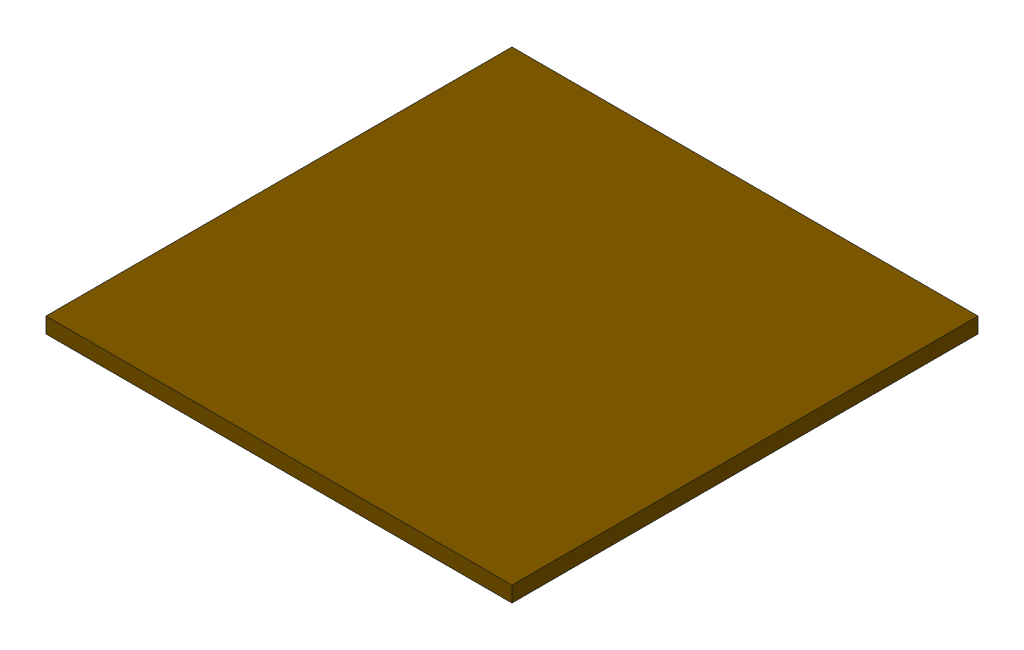
SolidWorks assembly Main, configuration Default. Lengths in mm.
Overall size (300 156.81 300).
28 component instances, 18 part files, 53 mates.
Components (placement in the parent):
- PCB Outline v2-1: PCB Outline v2 [Default] at (-204.6573 359.2856 0) x (-0.0002 0 1) z (-1 0 -0.0002) size (100 3 100)
- RolyPoly PCB v1 SLDWRKS-1: RolyPoly PCB v1 SLDWRKS [Default] at (-151.3038 354.2331 -67.2993) x (-0.0002 0 1) z (0 -1 0) size (100 100 1.64)
  - RolyPoly PCB v1.step-1: RolyPoly PCB v1.step [Default] at origin size (100 100 1.64)
    - Board.step-1: Board.step [Default] at origin size (100 100 1.5)
    - 1-copper.step-1: 1-copper.step [Default] at (0 0 1.5) size (91.04 84.59 0.07)
    - 16-copper.step-1: 16-copper.step [Default] at (0 0 -0.035) size (97.81 97.81 0.07)
    - 1-soldermask.step-1: 1-soldermask.step [Default] at (0 0 1.5) size (100 100 0.05)
    - 16-soldermask.step-1: 16-soldermask.step [Default] at origin size (100 100 0.05)
- N20 Motor Mount-1: N20 Motor Mount [Default] at (-210.7573 401.2856 3) x (1 0 0) z (0 0 -1) size (34.2 12 12)
- N20 Motor Mount-2: N20 Motor Mount [Default] at (-198.5573 401.2856 -3) x (-1 0 0) z (0 0 1) size (34.2 12 12)
- Motor2-1: Motor2 [Default] at (-198.5573 398.2856 -6.9) x (0 -1 0) z (0 0 -1) size (10 12 34)
- Motor2-2: Motor2 [Default] at (-210.7573 398.2856 6.9) x (0 -1 0) z (0 0 1) size (10 12 34)
- 18650 Battery Holder-1: 18650 Battery Holder [Default] at (-323.8149 384.2856 -340.7623) x (1 0 0) z (0 0 -1) size (87.56 15 40.53)
- Wheel 34mm-1: Wheel 34mm [Default] at (-204.7282 393.0919 -37.6) x (0 1 0) z (-1 0 0) size (34.66 8.6 34.65)
- Wheel 34mm-2: Wheel 34mm [Default] at (-204.5865 393.0919 37.6) x (0 1 0) z (1 0 0) size (34.66 8.6 34.65)
- Body v1-1: Body v1 [Default] at (-204.6573 384.2856 0) x (0 0 1) z (-1 0 0) size (89.8 4 100)
- Sphere 120mm-1: Sphere 120mm [Default] at (-144.4579 366.7924 0) size (120 120 60)
- Support-1: Support [Default] at (-249.6573 388.2856 -20.1) x (1 0 0) z (0 0 -1) size (90 17.04 5)
- Support-2: Support [Default] at (-159.6573 388.2856 20.1) x (-1 0 0) z (0 0 1) size (90 17.04 5)
- Sphere 120mm-2: Sphere 120mm [Default] at (-259.8815 343.8094 0) x (-0.923728 -0.383049 0) z (0 0 -1) size (120 120 60)
- TopSupport-1: TopSupport [Default] at (-249.6573 384.2856 20.6) size (90 22 4)
- TopSupport-2: TopSupport [Default] at (-249.6573 384.2856 -24.6) size (90 22 4)
- UpperShellSupport-2: UpperShellSupport [Default] at (-204.698 367.2856 1.8389) x (0.044077 0 -0.999028) z (-0.999028 0 -0.044077) size (34.21 60.05 116.13)
- Spacer-1: Spacer [Default] at (-160.2106 354.2856 16.5189) x (0.026144 0 -0.999658) z (0.999658 0 0.026144) size (6 5 6)
- Spacer-2: Spacer [Default] at (-246.5673 354.2856 -0.0084) size (6 5 6)
- Spacer-3: Spacer [Default] at (-158.9348 354.2856 -12.6908) size (6 5 6)
- UpperWheel-1: UpperWheel [Default] at (-204.7862 319.4856 3.8369) x (0.044077 0 -0.999028) z (0.999028 0 0.044077) size (4 19.4 19.4)
- RenderBase-1: RenderBase [Default] at (-344.3442 426.5241 157.9704) size (300 10 300)
Mates (geometry in assembly coordinates):
- Coincident13: coincident anti-aligned: plane of N20 Motor Mount-2 through (-198.5573 389.2856 -3) normal (-1 0 0); plane of Motor2-1 through (-198.5573 396.2856 -21.9) normal (1 0 0)
- Coincident16: coincident anti-aligned: plane of N20 Motor Mount-1 through (-210.7573 389.2856 3) normal (1 0 0); plane of Motor2-2 through (-210.7573 396.2856 21.9) normal (-1 0 0)
- Coincident18: coincident anti-aligned: plane of Motor2-2 through (-203.8663 398.2856 40.9) normal (1 0 0); plane of Wheel 34mm-2 through (-203.8663 393.0919 40.9) normal (-1 0 0)
- Coincident19: coincident aligned: plane of Motor2-2 through (-210.7573 398.2856 40.9) normal (0 0 1); plane of Wheel 34mm-2 through (-204.5865 393.0919 40.9) normal (0 0 1)
- Coincident20: coincident aligned: plane of Motor2-1 through (-198.5573 398.2856 -40.9) normal (0 0 -1); plane of Wheel 34mm-1 through (-204.7282 393.0919 -40.9) normal (0 0 -1)
- Coincident21: coincident anti-aligned: plane of Motor2-1 through (-205.4484 398.2856 -40.9) normal (-1 0 0); plane of Wheel 34mm-1 through (-205.4484 393.0919 -40.9) normal (1 0 0)
- Coincident22: coincident anti-aligned: plane of N20 Motor Mount-1 through (-210.7573 398.2856 3) normal (0 -1 0); plane of Motor2-2 through (-208.7573 398.2856 21.9) normal (0 1 0)
- Coincident23: coincident anti-aligned: plane of N20 Motor Mount-2 through (-198.5573 398.2856 -3) normal (0 -1 0); plane of Motor2-1 through (-200.5573 398.2856 -21.9) normal (0 1 0)
- Coincident44: coincident anti-aligned: plane of Sphere 120mm-1 through (-204.4579 366.7924 0) normal (0 0 -1)
- Distance4: distance = 26 mm aligned: plane of Body v1-1 through (-204.6573 388.2856 26) normal (0 0 1)
- Coincident50: coincident aligned: plane of Wheel 34mm-1 through (-204.7282 393.5919 -34.3) normal (0 -1 0); plane of Wheel 34mm-2 through (-204.5865 393.5919 34.3) normal (0 -1 0)
- Concentric22: concentric anti-aligned: circle of PCB Outline v1-1; circle of RolyPoly PCB v1 SLDWRKS-1/RolyPoly PCB v1.step-1/1-soldermask.step-1
- Concentric23: concentric aligned: circle of PCB Outline v1-1; circle of RolyPoly PCB v1 SLDWRKS-1/RolyPoly PCB v1.step-1/16-soldermask.step-1
- Concentric24: concentric aligned: cylinder of PCB Outline v1-1 through (-158.9348 362.2856 -12.6908) axis (0 -1 0) radius 1.5; cylinder of Spacer-3 through (-158.9348 359.2856 -12.6908) axis (0 -1 0) radius 1.65
- Coincident84: coincident anti-aligned: plane of PCB Outline v1-1 through (-204.6573 359.2856 0) normal (0 -1 0); plane of Spacer-3 through (-158.9348 359.2856 -12.6908) normal (0 1 0)
- Concentric25: concentric aligned: cylinder of PCB Outline v1-1 through (-160.2106 362.2856 16.5189) axis (0 -1 0) radius 1.5; cylinder of Spacer-1 through (-160.2106 359.2856 16.5189) axis (0 -1 0) radius 1.65
- Coincident85: coincident anti-aligned: plane of PCB Outline v1-1 through (-204.6573 359.2856 0) normal (0 -1 0); plane of Spacer-1 through (-160.2106 359.2856 16.5189) normal (0 1 0)
- Concentric26: concentric aligned: cylinder of PCB Outline v1-1 through (-246.5673 362.2856 -0.0084) axis (0 -1 0) radius 1.5; cylinder of Spacer-2 through (-246.5673 359.2856 -0.0084) axis (0 -1 0) radius 1.65
- Coincident86: coincident anti-aligned: plane of PCB Outline v1-1 through (-204.6573 359.2856 0) normal (0 -1 0); plane of Spacer-2 through (-246.5673 359.2856 -0.0084) normal (0 1 0)
- Concentric27: concentric anti-aligned: cylinder of RolyPoly PCB v1 SLDWRKS-1/RolyPoly PCB v1.step-1/Board.step-1 through (-246.5673 353.5361 -0.0084) axis (0 1 0) radius 1.5; cylinder of Spacer-2 through (-246.5673 359.2856 -0.0084) axis (0 -1 0) radius 1.65
- Coincident87: coincident anti-aligned: plane of RolyPoly PCB v1 SLDWRKS-1/RolyPoly PCB v1.step-1/16-soldermask.step-1 through (-204.6573 354.2856 0) normal (0 1 0); plane of Spacer-3 through (-158.9348 354.2856 -12.6908) normal (0 -1 0)
- Concentric37: concentric anti-aligned: circle of Sphere 120mm-1; circle of Sphere 120mm-2
- Coincident90: coincident anti-aligned: plane of Sphere 120mm-1 through (-204.4579 366.7924 0) normal (0 0 -1); plane of Sphere 120mm-2 through (-204.4579 366.7924 0) normal (0 0 1)
- Width1: width aligned: plane of 18650 Battery Holder-1 through (-166.1073 369.2856 -340.7623) normal (1 0 0); plane of 18650 Battery Holder-1 through (-243.2073 369.2856 -340.7623) normal (-1 0 0); plane of Body v1-1 through (-226.6573 388.2856 0) normal (1 0 0); plane of Body v1-1 through (-182.6573 388.2856 0) normal (-1 0 0)
- Coincident91: coincident anti-aligned: plane of 18650 Battery Holder-1 through (-323.8149 384.2856 -340.7623) normal (0 1 0); plane of Body v1-1 through (-204.6573 384.2856 0) normal (0 -1 0)
- Concentric38: concentric aligned: cylinder of Body v1-1 through (-163.6573 388.2856 -22.6) axis (0 -1 0) radius 1.5; cylinder of Support-1 through (-163.6573 403.2856 -22.6) axis (0 -1 0) radius 1.5
- Coincident93: coincident anti-aligned: plane of Body v1-1 through (-204.6573 388.2856 0) normal (0 1 0); plane of Support-1 through (-249.6573 388.2856 -25.1) normal (0 -1 0)
- Concentric39: concentric aligned: cylinder of Body v1-1 through (-245.6573 388.2856 -22.6) axis (0 -1 0) radius 1.5; cylinder of Support-1 through (-245.6573 403.2856 -22.6) axis (0 -1 0) radius 1.5
- Coincident94: coincident anti-aligned: plane of Body v1-1 through (-204.6573 388.2856 0) normal (0 1 0); plane of Support-2 through (-159.6573 388.2856 25.1) normal (0 -1 0)
- Concentric40: concentric aligned: cylinder of Body v1-1 through (-163.6573 388.2856 22.6) axis (0 -1 0) radius 1.5; cylinder of Support-2 through (-163.6573 403.2856 22.6) axis (0 -1 0) radius 1.5
- Concentric41: concentric aligned: cylinder of Body v1-1 through (-245.6573 388.2856 22.6) axis (0 -1 0) radius 1.5; cylinder of Support-2 through (-245.6573 403.2856 22.6) axis (0 -1 0) radius 1.5
- Coincident96: coincident anti-aligned: plane of Motor2-2 through (-208.7573 388.2856 21.9) normal (0 -1 0); plane of Body v1-1 through (-204.6573 388.2856 0) normal (0 1 0)
- Concentric42: concentric aligned: cylinder of N20 Motor Mount-1 through (-190.5573 391.9856 10) axis (0 -1 0) radius 1.5; cylinder of Body v1-1 through (-190.5573 388.2856 10) axis (0 -1 0) radius 1.5
- Concentric43: concentric aligned: cylinder of N20 Motor Mount-1 through (-218.7573 391.9856 10) axis (0 -1 0) radius 1.5; cylinder of Body v1-1 through (-218.7573 388.2856 10) axis (0 -1 0) radius 1.5
- Concentric44: concentric aligned: cylinder of N20 Motor Mount-2 through (-218.7573 391.9856 -10) axis (0 -1 0) radius 1.5; cylinder of Body v1-1 through (-218.7573 388.2856 -10) axis (0 -1 0) radius 1.5
- Coincident98: coincident anti-aligned: plane of Motor2-1 through (-200.5573 388.2856 -21.9) normal (0 -1 0); plane of Body v1-1 through (-204.6573 388.2856 0) normal (0 1 0)
- Concentric45: concentric aligned: cylinder of N20 Motor Mount-2 through (-190.5573 391.9856 -10) axis (0 -1 0) radius 1.5; cylinder of Body v1-1 through (-190.5573 388.2856 -10) axis (0 -1 0) radius 1.5
- Width2: width anti-aligned: plane of Body v1-1 through (-204.6573 388.2856 -26) normal (0 0 -1); plane of 18650 Battery Holder-1 through (-204.6573 388.2856 26) normal (0 0 1); plane of Body v1-1 through (-323.8149 369.2856 20.2629) normal (0 0 1); plane of 18650 Battery Holder-1 through (-323.8149 369.2856 -20.2629) normal (0 0 -1)
- Concentric46: concentric anti-aligned: cylinder of Body v1-1 through (-163.6573 388.2856 22.6) axis (0 -1 0) radius 1.5; cylinder of TopSupport-1 through (-163.6573 369.2856 22.6) axis (0 1 0) radius 1.6
- Concentric47: concentric anti-aligned: cylinder of Body v1-1 through (-245.6573 388.2856 22.6) axis (0 -1 0) radius 1.5; cylinder of TopSupport-1 through (-245.6573 369.2856 22.6) axis (0 1 0) radius 1.6
- Coincident99: coincident anti-aligned: plane of Body v1-1 through (-204.6573 384.2856 0) normal (0 -1 0); plane of TopSupport-1 through (-249.6573 384.2856 24.6) normal (0 1 0)
- Coincident100: coincident anti-aligned: plane of PCB Outline v1-1 through (-204.6573 362.2856 0) normal (0 1 0); plane of TopSupport-1 through (-249.6573 362.2856 24.6) normal (0 -1 0)
- Concentric48: concentric aligned: circle of PCB Outline v1-1; circle of Body v1-1
- Concentric49: concentric anti-aligned: cylinder of Body v1-1 through (-245.6573 388.2856 -22.6) axis (0 -1 0) radius 1.5; cylinder of TopSupport-2 through (-245.6573 369.2856 -22.6) axis (0 1 0) radius 1.6
- Concentric50: concentric anti-aligned: cylinder of Body v1-1 through (-163.6573 388.2856 -22.6) axis (0 -1 0) radius 1.5; cylinder of TopSupport-2 through (-163.6573 369.2856 -22.6) axis (0 1 0) radius 1.6
- Coincident103: coincident anti-aligned: plane of Body v1-1 through (-204.6573 384.2856 0) normal (0 -1 0); plane of TopSupport-2 through (-249.6573 384.2856 -20.6) normal (0 1 0)
- Concentric54: concentric anti-aligned: cylinder of PCB Outline v2-1 through (-160.2106 362.2856 16.5189) axis (0 -1 0) radius 1.5; cylinder of UpperShellSupport-2 through (-160.2106 365.2856 16.5189) axis (0 1 0) radius 1.5
- Concentric55: concentric anti-aligned: cylinder of PCB Outline v2-1 through (-246.5673 362.2856 -0.0084) axis (0 -1 0) radius 1.5; cylinder of UpperShellSupport-2 through (-246.5673 370.2856 -0.0084) axis (0 1 0) radius 1.5
- Concentric56: concentric aligned: cylinder of UpperShellSupport-2 through (-205.0507 317.7856 9.8311) axis (0.044077 0 -0.999028) radius 1.5; cylinder of UpperWheel-1 through (-204.6099 317.7856 -0.1592) axis (0.044077 0 -0.999028) radius 1.7
- Width3: width aligned: plane of UpperWheel-1 through (-204.7862 319.4856 3.8369) normal (-0.044077 0 0.999028); plane of UpperShellSupport-2 through (-204.6099 319.4856 -0.1592) normal (0.044077 0 -0.999028); plane of UpperWheel-1 through (-204.5217 297.2856 -2.1573) normal (-0.044077 0 0.999028); plane of UpperShellSupport-2 through (-204.8744 297.2856 5.835) normal (0.044077 0 -0.999028)
- Distance6: distance = 13.8 mm anti-aligned: plane of Motor2-1 through (-200.5573 396.2856 -6.9) normal (0 0 1); plane of Motor2-2 through (-208.7573 396.2856 6.9) normal (0 0 -1)
- Width6: width aligned: plane of Motor2-1 through (-200.5573 396.2856 -6.9) normal (0 0 1); plane of Support-1 through (-208.7573 396.2856 6.9) normal (0 0 -1); plane of Motor2-2 through (-249.6573 388.2856 -20.1) normal (0 0 1); plane of Support-2 through (-159.6573 388.2856 20.1) normal (0 0 -1)
- Coincident108: coincident anti-aligned: plane of PCB Outline v2-1 through (-204.6573 362.2856 0) normal (0 1 0); plane of UpperShellSupport-2 through (-160.0131 362.2856 -12.7157) normal (0 -1 0)
